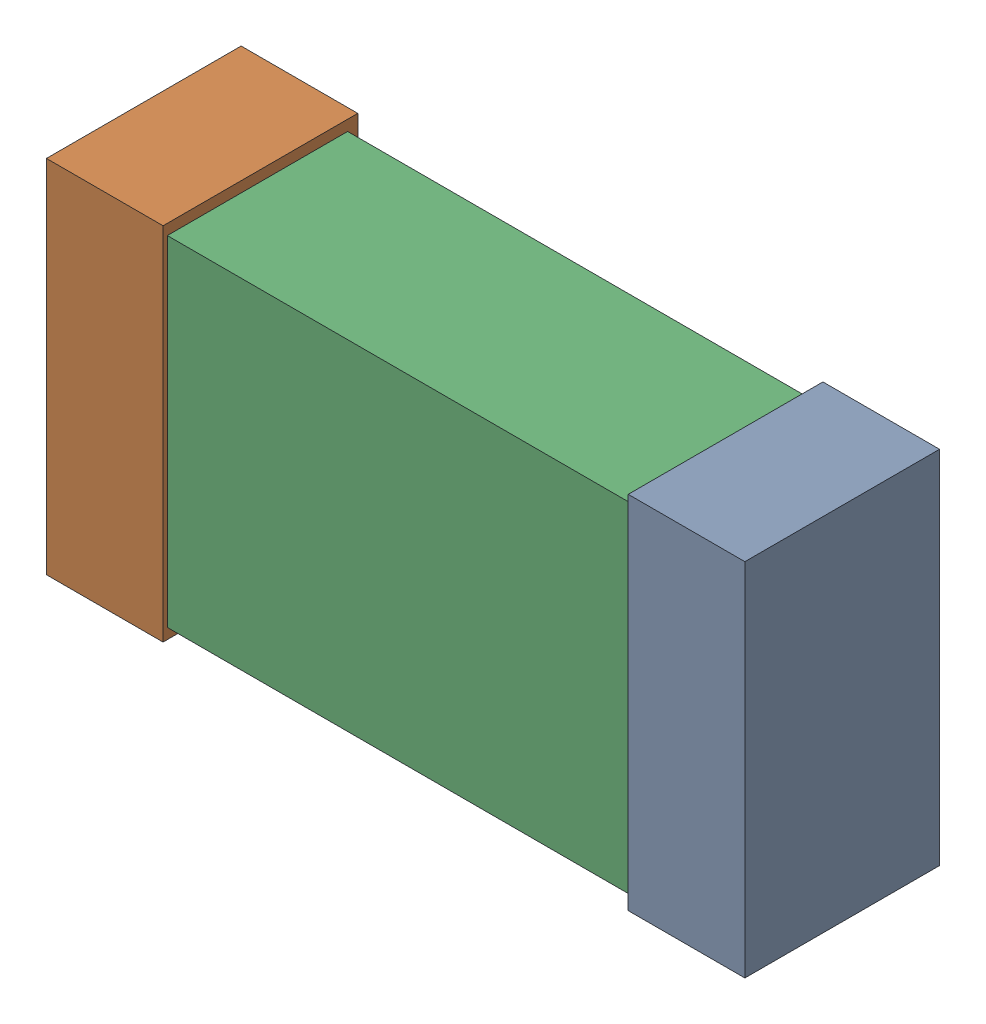
SolidWorks assembly C43, configuration Default. Lengths in mm.
Overall size (1.65 0.85 0.46).
6 component instances, 2 part files, 0 mates.
Components (placement in the parent):
- 432120464-1: 432120464 [Default] at (43.8858 10.4867 0.001) size (0.28 0.85 0.46)
  - Extruded (11)-1: Extruded (11) [Default] at origin size (0.28 0.85 0.46)
- 432120464_1-1: 432120464_1 [Default] at (42.5143 10.4867 0.001) size (0.28 0.85 0.46)
  - Extruded (11)-1: Extruded (11) [Default] at origin size (0.28 0.85 0.46)
- 432120720-1: 432120720 [Default] at (43.2001 10.4867 0.025) size (1.5 0.8 0.42)
  - Extruded (12)-1: Extruded (12) [Default] at origin size (1.5 0.8 0.42)
